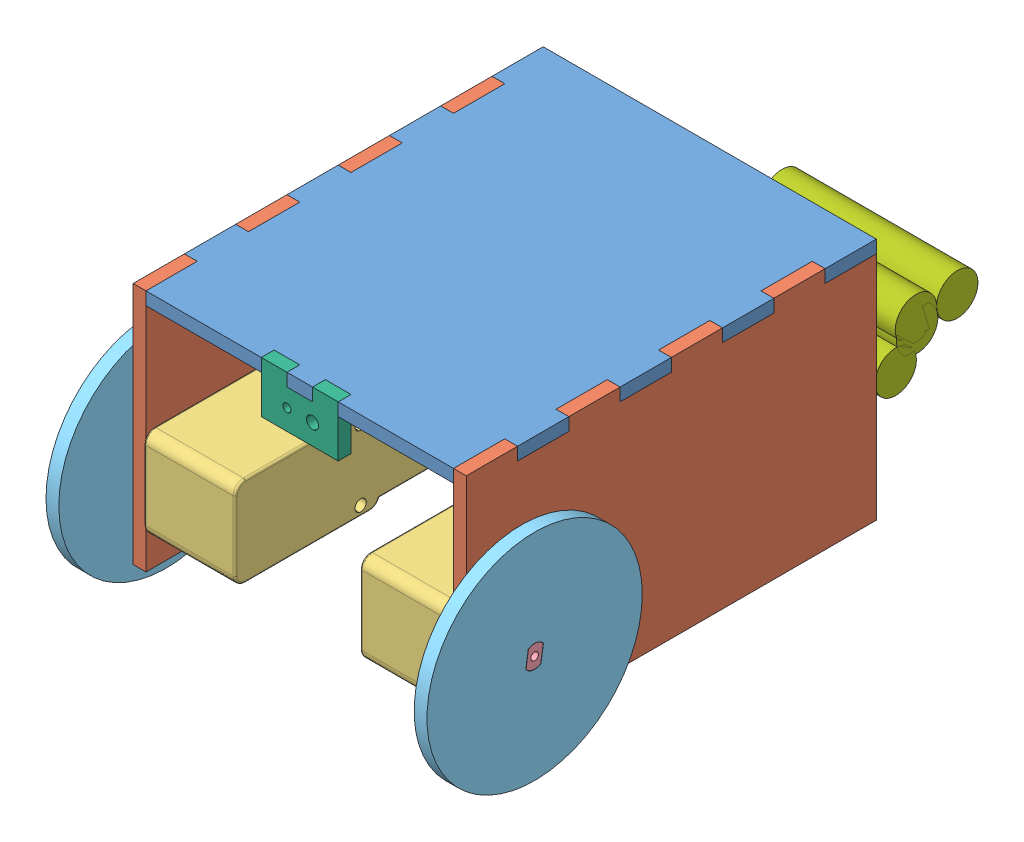
SolidWorks assembly Box, configuration Default. Lengths in mm.
Overall size (94.4 71.59 166.14).
18 component instances, 9 part files, 32 mates.
Components (placement in the parent):
- TopPanel-1: TopPanel [Default] at (-79.375 -3.175 0) size (82.55 3.17 101.6)
- SidePanel-1: SidePanel [Default] at (-3.175 -60.325 0) size (3.17 60.32 101.6)
- SidePanel-2: SidePanel [Default] at (-82.55 -60.325 0) size (3.17 60.32 101.6)
- motor-1: motor [Default] at (-25.775 -52.425 0.508) size (24.6 22.3 64.4)
- motor-2: motor [Default] at (-56.775 -30.125 0.508) x (-1 0 0) z (0 0 1) size (24.6 22.3 64.4)
- motor shaft-1: motor shaft [Default] at (-4.445 -41.275 -11) x (0 -0.989022 0.147769) z (1 0 0) size (5.5 3.7 10.37)
- motor shaft-2: motor shaft [Default] at (-78.105 -41.275 -11) x (0 -0.004727 0.999989) z (-1 0 0) size (5.5 3.7 10.37)
- wheel-1: wheel [Default] at (-88.475 -41.275 -11) x (0 0.004727 -0.999989) z (1 0 0) size (53.34 53.34 3.17)
- wheel-2: wheel [Default] at (5.925 -41.275 -11) x (0 -0.989022 0.147769) z (-1 0 0) size (53.34 53.34 3.17)
- ir holder-1: ir holder [Default] at (-50.8 -12.7 -3.175) size (19.05 12.7 3.17)
- AAA battery-1: AAA battery [Default] at (-18.161 -42.6111 -129.8759) x (0 -0.179244 0.983805) z (-1 0 0) size (10.26 10.26 43.43)
- AAA battery-2: AAA battery [Default] at (-18.161 -40.0558 -139.8143) x (0 0.867016 -0.49828) z (-1 0 0) size (10.26 10.26 43.43)
- AAA battery-3: AAA battery [Default] at (-18.161 -40.0558 -129.5527) x (0 0.617443 0.786615) z (-1 0 0) size (10.26 10.26 43.43)
- AAA battery-4: AAA battery [Default] at (-18.161 -49.0193 -124.5571) x (0 -0.440657 -0.897676) z (-1 0 0) size (10.26 10.26 43.43)
- electronics board-1: electronics board [Default] at (-52.5826 4.952 -87.8084) x (-1 0 0) z (0 0 1) size (57.15 4.64 38.1)
  - h bridge-1: h bridge [Default] at (-15.5412 9.7145 -4.546) size (19.3 3.05 6.63)
  - electronics board-1: electronics board [Default] at (-39.8826 8.127 24.3084) size (57.15 1.59 38.1)
  - h bridge-2: h bridge [Default] at (-15.5412 9.7145 21.1334) size (19.3 3.05 6.63)
Mates (geometry in assembly coordinates):
- Coincident1: coincident aligned: plane of TopPanel-1 through (-79.375 0 0) normal (0 0 1); plane of SidePanel-1 through (0 -60.325 0) normal (0 0 1)
- Coincident2: coincident aligned: plane of TopPanel-1 through (-79.375 0 0) normal (0 0 1); plane of SidePanel-2 through (-79.375 -60.325 0) normal (0 0 1)
- Coincident3: coincident aligned: plane of TopPanel-1 through (-79.375 0 0) normal (0 1 0); plane of SidePanel-2 through (-79.375 0 0) normal (0 1 0)
- Coincident4: coincident aligned: plane of TopPanel-1 through (-79.375 0 0) normal (0 1 0); plane of SidePanel-1 through (0 0 -25.4) normal (0 1 0)
- Coincident5: coincident aligned: plane of TopPanel-1 through (-82.55 0 -25.4) normal (-1 0 0); plane of SidePanel-2 through (-82.55 -60.325 0) normal (-1 0 0)
- Coincident6: coincident aligned: plane of TopPanel-1 through (0 0 -12.7) normal (1 0 0); plane of SidePanel-1 through (0 -60.325 0) normal (1 0 0)
- Concentric1: concentric anti-aligned: cylinder of motor-1 through (-4.445 -41.275 -11) axis (1 0 0) radius 2.75; cylinder of motor shaft-1 through (5.925 -41.275 -11) axis (-1 0 0) radius 2.75
- Coincident7: coincident anti-aligned: plane of motor-1 through (-4.445 -41.275 -11) normal (1 0 0); plane of motor shaft-1 through (-4.445 -41.275 -11) normal (-1 0 0)
- Concentric2: concentric anti-aligned: cylinder of motor-2 through (-78.105 -41.275 -11) axis (-1 0 0) radius 2.75; cylinder of motor shaft-2 through (-88.475 -41.275 -11) axis (1 0 0) radius 2.75
- Coincident8: coincident anti-aligned: plane of motor-2 through (-78.105 -41.275 -11) normal (-1 0 0); plane of motor shaft-2 through (-78.105 -41.275 -11) normal (1 0 0)
- Concentric3: concentric aligned: cylinder of SidePanel-2 through (-82.551 -41.275 -11) axis (1 0 0) radius 2.877; cylinder of motor shaft-2 through (-88.475 -41.275 -11) axis (1 0 0) radius 2.75
- Concentric6: concentric aligned: cylinder of SidePanel-2 through (-82.551 -41.275 -22) axis (1 0 0) radius 2; cylinder of motor-2 through (-81.375 -41.275 -22) axis (1 0 0) radius 2
- Coincident9: coincident anti-aligned: plane of SidePanel-2 through (-79.375 -60.325 0) normal (1 0 0); plane of motor-2 through (-79.375 -30.125 0.508) normal (-1 0 0)
- Concentric7: concentric anti-aligned: cylinder of SidePanel-1 through (-3.176 -41.275 -11) axis (1 0 0) radius 2.877; cylinder of motor shaft-1 through (5.925 -41.275 -11) axis (-1 0 0) radius 2.75
- Concentric9: concentric anti-aligned: cylinder of SidePanel-1 through (-3.176 -41.275 -22) axis (1 0 0) radius 2; cylinder of motor-1 through (-1.175 -41.275 -22) axis (-1 0 0) radius 2
- Coincident10: coincident anti-aligned: plane of SidePanel-1 through (-3.175 -60.325 0) normal (-1 0 0); plane of motor-1 through (-3.175 -52.425 0.508) normal (1 0 0)
- Coincident11: coincident aligned: plane of TopPanel-1 through (-79.375 0 0) normal (0 0 1); plane of assembly through (0 0 0) normal (0 0 1)
- Coincident12: coincident aligned: plane of TopPanel-1 through (-79.375 0 0) normal (0 1 0); plane of assembly through (0 0 0) normal (0 1 0)
- Coincident13: coincident aligned: plane of SidePanel-1 through (0 -60.325 0) normal (1 0 0); plane of assembly through (0 0 0) normal (1 0 0)
- Concentric10: concentric anti-aligned: cylinder of motor shaft-2 through (-88.475 -41.275 -11) axis (1 0 0) radius 2.75; cylinder of wheel-1 through (-85.3 -41.275 -11) axis (-1 0 0) radius 2.8067
- Coincident14: coincident aligned: plane of motor shaft-2 through (-88.475 -41.275 -11) normal (-1 0 0); plane of wheel-1 through (-88.475 -41.275 -11) normal (-1 0 0)
- Concentric11: concentric anti-aligned: cylinder of motor shaft-1 through (5.925 -41.275 -11) axis (-1 0 0) radius 2.75; cylinder of wheel-2 through (2.75 -41.275 -11) axis (1 0 0) radius 2.8067
- Coincident15: coincident aligned: plane of motor shaft-1 through (5.925 -41.275 -11) normal (1 0 0); plane of wheel-2 through (5.925 -41.275 -11) normal (1 0 0)
- Parallel1: parallel anti-aligned: plane of motor shaft-1 through (5.925 -39.536 -13.1304) normal (0 -0.147769 -0.989022); plane of wheel-2 through (2.75 -41.5565 -12.8841) normal (0 0.147769 0.989022)
- Parallel2: parallel anti-aligned: plane of motor shaft-2 through (-88.475 -39.4154 -13.0259) normal (0 0.999989 0.004727); plane of wheel-1 through (-85.3 -39.37 -10.991) normal (0 -0.999989 -0.004727)
- GearMate1: gear = 53.34 : 53.34 mm: cylinder of wheel-1 through (-85.3 -41.275 -11) axis (-1 0 0) radius 26.67; cylinder of wheel-2 through (2.75 -41.275 -11) axis (1 0 0) radius 26.67
- Coincident18: coincident anti-aligned: plane of TopPanel-1 through (-79.375 -3.175 0) normal (0 -1 0); plane of ir holder-1 through (-44.45 -3.175 0) normal (0 1 0)
- Coincident19: coincident anti-aligned: plane of TopPanel-1 through (-38.1 -3.175 0) normal (1 0 0); plane of ir holder-1 through (-38.1 -3.175 0) normal (-1 0 0)
- Coincident20: coincident aligned: plane of TopPanel-1 through (-79.375 0 0) normal (0 0 1); plane of ir holder-1 through (-50.8 -12.7 0) normal (0 0 1)
- Coincident32: coincident anti-aligned: plane of TopPanel-1 through (-79.375 -3.175 0) normal (0 -1 0); plane of electronics board-1/electronics board-1 through (-12.7 -3.175 -63.5) normal (0 1 0)
- Coincident33: coincident aligned: plane of TopPanel-1 through (0 0 -101.6) normal (0 0 -1); plane of electronics board-1/electronics board-1 through (-12.7 -4.7625 -101.6) normal (0 0 -1)
- Distance2: distance = 9.525 mm anti-aligned: plane of SidePanel-1 through (-3.175 -60.325 0) normal (-1 0 0); plane of electronics board-1/electronics board-1 through (-12.7 -4.7625 -63.5) normal (1 0 0)
